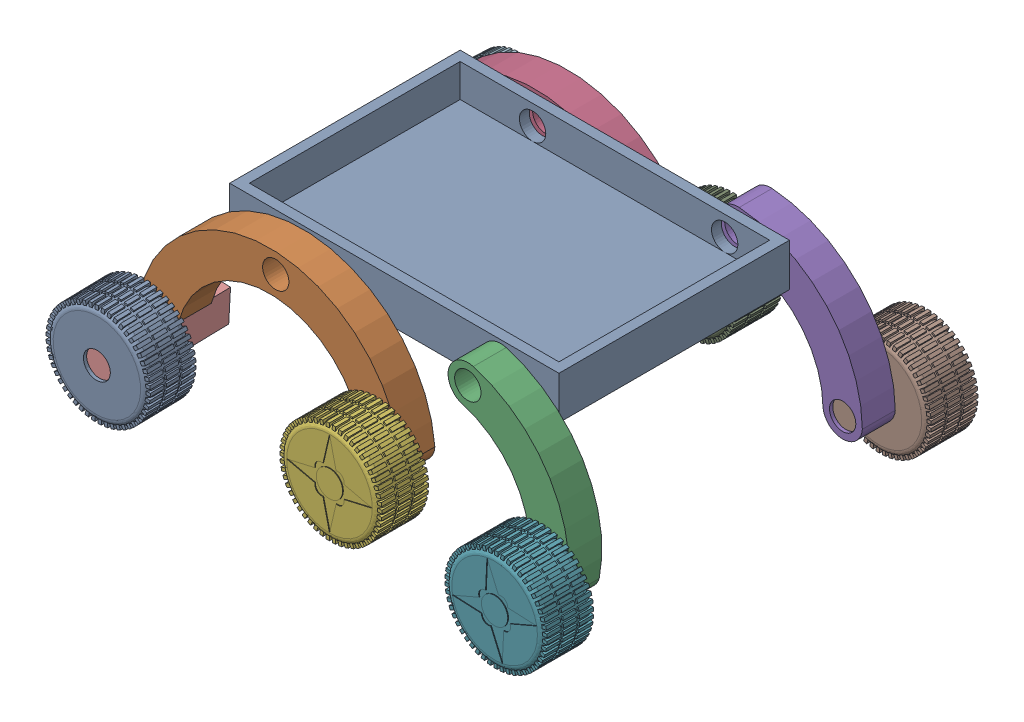
SolidWorks assembly Ensamble Rover, configuration Predeterminado. Lengths in mm.
Overall size (834.42 334.91 656.75).
13 component instances, 6 part files, 24 mates.
Components (placement in the parent):
- Base-1: Base [Predeterminado] at (15.4526 -1.8363 175) size (500 65 350)
- Soporte rueda delantera-1: Soporte rueda delantera [Predeterminado] at (-109.5474 33.1637 405) x (-0.998445 0.055744 0) z (0 0 -1) size (400 225 50)
- Soporte rueda trasera-1: Soporte rueda trasera [Predeterminado] at (182.1192 33.1637 355) x (0.961241 -0.275711 0) z (0 0 1) size (230 215 50)
- Soporte rueda delantera-2: Soporte rueda delantera [Predeterminado] at (-109.5474 33.1637 -5) x (-0.995451 0.095278 0) z (0 0 -1) size (400 225 50)
- Soporte rueda trasera-2: Soporte rueda trasera [Predeterminado] at (182.1192 33.1637 -55) x (0.997699 -0.067793 0) z (0 0 1) size (230 215 50)
- Rueda-1: Rueda [Predeterminado] at (52.1054 -121.0873 410) x (1 0.000085 0) z (0 0 1) size (155 155.01 125)
- Rueda-2: Rueda [Predeterminado] at (302.795 -162.6994 410) x (0.983835 0.179075 0) z (0 0 1) size (155 155.01 125)
- Rueda-3: Rueda [Predeterminado] at (341.2202 -133.0045 -60) x (-0.923728 -0.383049 0) z (0 0 -1) size (155 155.01 125)
- Rueda-4: Rueda [Predeterminado] at (45.8638 -127.374 -60) x (-0.923728 -0.383049 0) z (0 0 -1) size (155 155.01 125)
- Soporte giro rueda delantera-1: Soporte giro rueda delantera [Predeterminado] at (-290.1532 -152.0566 380) x (-0.998209 0.055731 0.021753) z (-0.021719 0.001213 -0.999763) size (50 50 175)
- Soporte giro rueda delantera-2: Soporte giro rueda delantera [Predeterminado] at (-297.3533 -144.7519 -30) x (0.993941 -0.095134 0.055049) z (-0.054798 0.005245 0.998484) size (50 50 175)
- Rueda delantera-1: Rueda delantera [Predeterminado] at (-288.3956 -120.495 -149.818) x (0.998497 0.000144 0.054798) z (-0.054798 0.005245 0.998484) size (155.01 155 75)
- Rueda delantera-2: Rueda delantera [Predeterminado] at (-287.7822 -127.1501 424.9894) x (-0.451827 0.892039 0.010897) z (0.021719 -0.001213 0.999763) size (155.01 155 75)
Mates (geometry in assembly coordinates):
- Concéntrica1: concentric aligned: cylinder of Base-1 through (-109.5474 33.1637 0) axis (0 0 1) radius 20; cylinder of Soporte rueda delantera-1 through (-109.5474 33.1637 355) axis (0 0 1) radius 20
- Distancia1: distance = 5 mm anti-aligned: plane of Soporte rueda delantera-1 through (52.1054 -121.0873 355) normal (0 0 -1); plane of Base-1 through (-234.5474 13.1637 350) normal (0 0 1)
- Concéntrica2: concentric anti-aligned: cylinder of Base-1 through (182.1192 33.1637 0) axis (0 0 1) radius 20; cylinder of Soporte rueda trasera-1 through (182.1192 33.1637 405) axis (0 0 -1) radius 20
- Distancia2: distance = 5 mm anti-aligned: plane of Soporte rueda trasera-1 through (182.1192 33.1637 355) normal (0 0 -1); plane of Base-1 through (-234.5474 13.1637 350) normal (0 0 1)
- Concéntrica3: concentric aligned: cylinder of Base-1 through (-109.5474 33.1637 0) axis (0 0 1) radius 20; cylinder of Soporte rueda delantera-2 through (-109.5474 33.1637 -55) axis (0 0 1) radius 20
- Distancia3: distance = 5 mm anti-aligned: plane of Base-1 through (-234.5474 13.1637 0) normal (0 0 -1); plane of Soporte rueda delantera-2 through (45.8638 -127.374 -5) normal (0 0 1)
- Concéntrica4: concentric anti-aligned: cylinder of Base-1 through (182.1192 33.1637 0) axis (0 0 1) radius 20; cylinder of Soporte rueda trasera-2 through (182.1192 33.1637 -5) axis (0 0 -1) radius 20
- Distancia5: distance = 5 mm anti-aligned: plane of Soporte rueda trasera-2 through (182.1192 33.1637 -5) normal (0 0 1); plane of Base-1 through (-234.5474 13.1637 0) normal (0 0 -1)
- Concéntrica5: concentric aligned: cylinder of Soporte rueda delantera-1 through (52.1054 -121.0873 355) axis (0 0 1) radius 20; cylinder of Rueda-1 through (52.1054 -121.0873 360) axis (0 0 1) radius 20
- Distancia6: distance = 5 mm anti-aligned: plane of Rueda-1 through (52.1054 -121.0873 410) normal (0 0 -1); plane of Soporte rueda delantera-1 through (52.1054 -121.0873 405) normal (0 0 1)
- Concéntrica6: concentric aligned: cylinder of Soporte rueda trasera-2 through (341.2202 -133.0045 -5) axis (0 0 -1) radius 20; cylinder of Rueda-3 through (341.2202 -133.0045 -10) axis (0 0 -1) radius 20
- Distancia7: distance = 5 mm anti-aligned: plane of Rueda-3 through (341.2202 -133.0045 -60) normal (0 0 1); plane of Soporte rueda trasera-2 through (182.1192 33.1637 -55) normal (0 0 -1)
- Concéntrica7: concentric anti-aligned: cylinder of Soporte rueda delantera-2 through (45.8638 -127.374 -55) axis (0 0 1) radius 20; cylinder of Rueda-4 through (45.8638 -127.374 -10) axis (0 0 -1) radius 20
- Distancia8: distance = 5 mm anti-aligned: plane of Rueda-4 through (45.8638 -127.374 -60) normal (0 0 1); plane of Soporte rueda delantera-2 through (45.8638 -127.374 -55) normal (0 0 -1)
- Concéntrica8: concentric anti-aligned: cylinder of Soporte rueda trasera-1 through (302.795 -162.6994 405) axis (0 0 -1) radius 20; cylinder of Rueda-2 through (302.795 -162.6994 360) axis (0 0 1) radius 20
- Distancia9: distance = 5 mm anti-aligned: plane of Rueda-2 through (302.795 -162.6994 410) normal (0 0 -1); plane of Soporte rueda trasera-1 through (182.1192 33.1637 405) normal (0 0 1)
- Concéntrica9: concentric anti-aligned: cylinder of Soporte rueda delantera-1 through (-290.1532 -152.0566 380) axis (0.055744 0.998445 0) radius 20; cylinder of Soporte giro rueda delantera-1 through (-287.366 -102.1344 380) axis (-0.055744 -0.998445 0) radius 20
- Coincidente10: coincident anti-aligned: plane of Soporte rueda delantera-1; plane of Soporte giro rueda delantera-1
- Concéntrica10: concentric anti-aligned: cylinder of Soporte rueda delantera-2 through (-297.3533 -144.7519 -30) axis (0.095278 0.995451 0) radius 20; cylinder of Soporte giro rueda delantera-2 through (-292.5894 -94.9793 -30) axis (-0.095278 -0.995451 0) radius 20
- Coincidente11: coincident anti-aligned: plane of Soporte rueda delantera-2 through (-262.7259 -97.8377 -55) normal (-0.095278 -0.995451 0); plane of Soporte giro rueda delantera-2 through (-292.5894 -94.9793 -30) normal (0.095278 0.995451 0)
- Concéntrica11: concentric aligned: cylinder of Soporte giro rueda delantera-2 through (-288.6696 -120.4688 -144.8256) axis (-0.054798 0.005245 0.998484) radius 20; cylinder of Rueda delantera-1 through (-288.3956 -120.495 -149.818) axis (-0.054798 0.005245 0.998484) radius 20
- Distancia10: distance = 5 mm anti-aligned: plane of Rueda delantera-1 through (-292.5054 -120.1016 -74.9318) normal (-0.054798 0.005245 0.998484); plane of Soporte giro rueda delantera-2 through (-265.5489 -97.5675 -68.5631) normal (0.054798 -0.005245 -0.998484)
- Concéntrica12: concentric aligned: cylinder of Soporte giro rueda delantera-1 through (-261.131 -128.638 491.6212) axis (-0.240248 0.013413 -0.970619) radius 20; cylinder of Rueda delantera-2 through (-259.9298 -128.7051 496.4743) axis (-0.240248 0.013413 -0.970619) radius 20
- Distancia11: distance = 5 mm anti-aligned: plane of Rueda delantera-2 through (-286.1533 -127.241 499.9716) normal (0.021719 -0.001213 0.999763); plane of Soporte giro rueda delantera-1 through (-311.4524 -100.7896 420.5344) normal (0.021719 -0.001213 0.999763)
